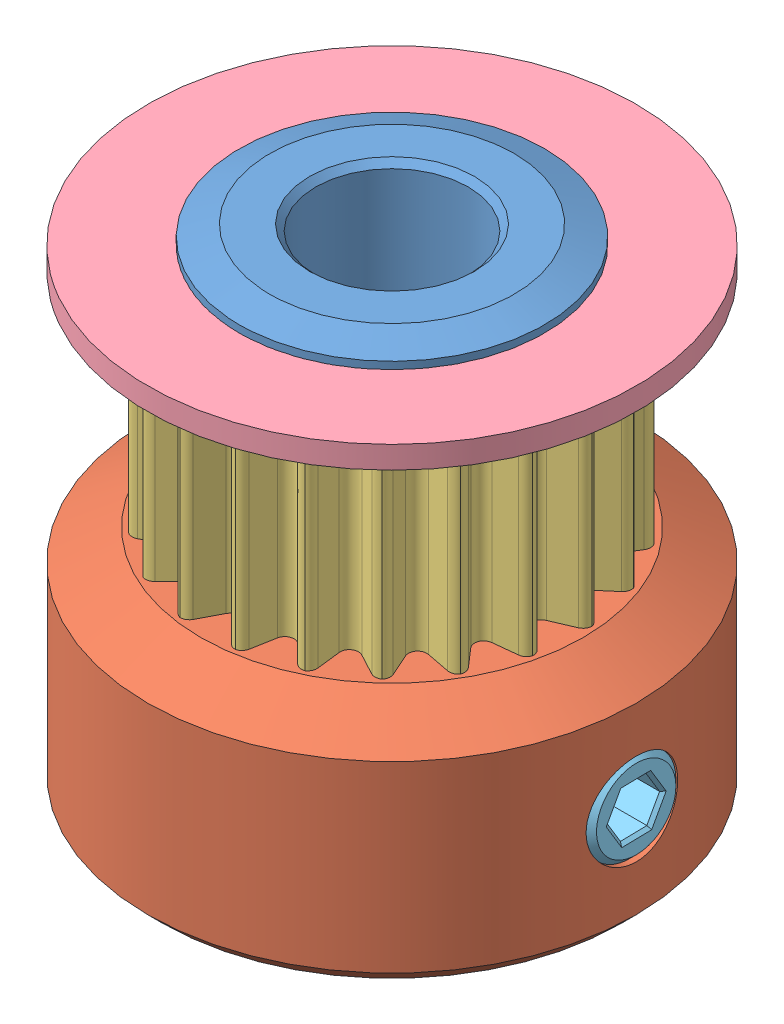
SolidWorks assembly GT2, configuration Default. Lengths in mm.
Overall size (22.15 16.1 22.15).
6 component instances, 5 part files, 11 mates.
Components (placement in the parent):
- GT2-1-1: GT2-1 [Default] at (2.7167 -5.018 1.9756) size (10 16.1 10)
- GT2-2-1: GT2-2 [Default] at (2.7167 -5.018 1.9756) size (16 7.5 16)
- GT2-3-1: GT2-3 [Default] at (2.7167 2.482 1.9756) size (12.18 7 12.15)
- GT2-4-1: GT2-4 [Default] at (2.7167 10.482 1.9756) x (-0.837169 0 -0.546944) z (-0.546944 0 0.837169) size (16 1 16)
- GT2-5-1: GT2-5 [Default] at (2.7167 -1.518 -1.9244) x (1 0 0) z (0 1 0) size (3 4.1 3)
- GT2-5-2: GT2-5 [Default] at (6.6167 -1.518 1.9756) x (0 -1 0) z (0 0 1) size (3 4.1 3)
Mates (geometry in assembly coordinates):
- Coincident1: coincident aligned: plane of GT2-1-1 through (2.7167 -5.018 1.9756) normal (0 -1 0); plane of GT2-2-1 through (2.7167 -5.018 1.9756) normal (0 -1 0)
- Concentric1: concentric aligned: cylinder of GT2-1-1 through (2.7167 11.082 1.9756) axis (0 -1 0) radius 5; cylinder of GT2-2-1 through (2.7167 2.482 1.9756) axis (0 -1 0) radius 5
- Coincident2: coincident anti-aligned: plane of GT2-2-1 through (2.7167 2.482 1.9756) normal (0 1 0); plane of GT2-3-1 through (2.7167 2.482 1.9756) normal (0 -1 0)
- Concentric2: concentric aligned: cylinder of GT2-1-1 through (2.7167 11.082 1.9756) axis (0 -1 0) radius 5; cylinder of GT2-3-1 through (2.7167 9.482 1.9756) axis (0 -1 0) radius 5
- Coincident3: coincident anti-aligned: plane of GT2-3-1 through (2.7167 9.482 1.9756) normal (0 1 0); plane of GT2-4-1 through (2.7167 9.482 1.9756) normal (0 -1 0)
- Concentric3: concentric anti-aligned: cylinder of GT2-1-1 through (2.7167 11.082 1.9756) axis (0 -1 0) radius 5; cylinder of GT2-4-1 through (2.7167 9.482 1.9756) axis (0 1 0) radius 5
- Concentric5: concentric aligned: cylinder of GT2-1-1 through (-2.2843 -1.518 1.9756) axis (1 0 0) radius 1.5; cylinder of GT2-2-1 through (-5.2843 -1.518 1.9756) axis (1 0 0) radius 1.5
- Concentric6: concentric: cylinder of GT2-2-1 through (2.7167 -1.518 9.9766) axis (0 0 -1) radius 1.5; cylinder of GT2-5-1 through (2.7167 -1.518 -6.0244) axis (0 0 1) radius 1.5
- Tangent1: tangent aligned: cylinder of GT2-2-1 through (2.7167 2.482 1.9756) axis (0 -1 0) radius 8; plane of GT2-5-1 through (2.7167 -1.518 -6.0244) normal (0 0 -1)
- Concentric7: concentric: cylinder of GT2-2-1 through (-5.2843 -1.518 1.9756) axis (1 0 0) radius 1.5; cylinder of GT2-5-2 through (10.7167 -1.518 1.9756) axis (-1 0 0) radius 1.5
- Tangent2: tangent aligned: cylinder of GT2-2-1 through (2.7167 2.482 1.9756) axis (0 -1 0) radius 8; plane of GT2-5-2 through (10.7167 -1.518 1.9756) normal (1 0 0)
